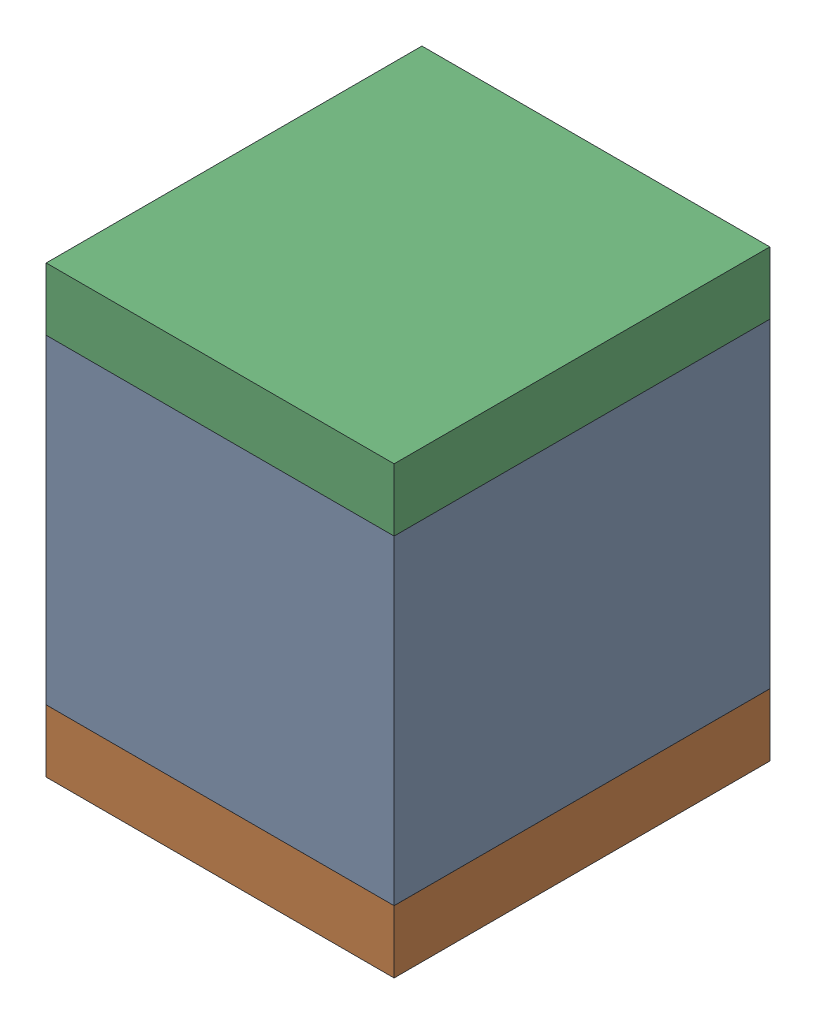
SolidWorks assembly C15, configuration ﾃﾞﾌｫﾙﾄ. Lengths in mm.
Overall size (2.5 3.2 2.7).
6 component instances, 2 part files, 0 mates.
Components (placement in the parent):
- 689260016-1: 689260016 [ﾃﾞﾌｫﾙﾄ] at (58 58.5 0) size (2.5 2.3 2.7)
  - Extruded_6-1: Extruded_6 [ﾃﾞﾌｫﾙﾄ] at origin size (2.5 2.3 2.7)
- 689260152-1: 689260152 [ﾃﾞﾌｫﾙﾄ] at (58.0001 57.125 0) size (2.5 0.45 2.7)
  - Extruded_7-1: Extruded_7 [ﾃﾞﾌｫﾙﾄ] at origin size (2.5 0.45 2.7)
- 689260152-2: 689260152 [ﾃﾞﾌｫﾙﾄ] at (58.0001 59.875 0) size (2.5 0.45 2.7)
  - Extruded_7-1: Extruded_7 [ﾃﾞﾌｫﾙﾄ] at origin size (2.5 0.45 2.7)
